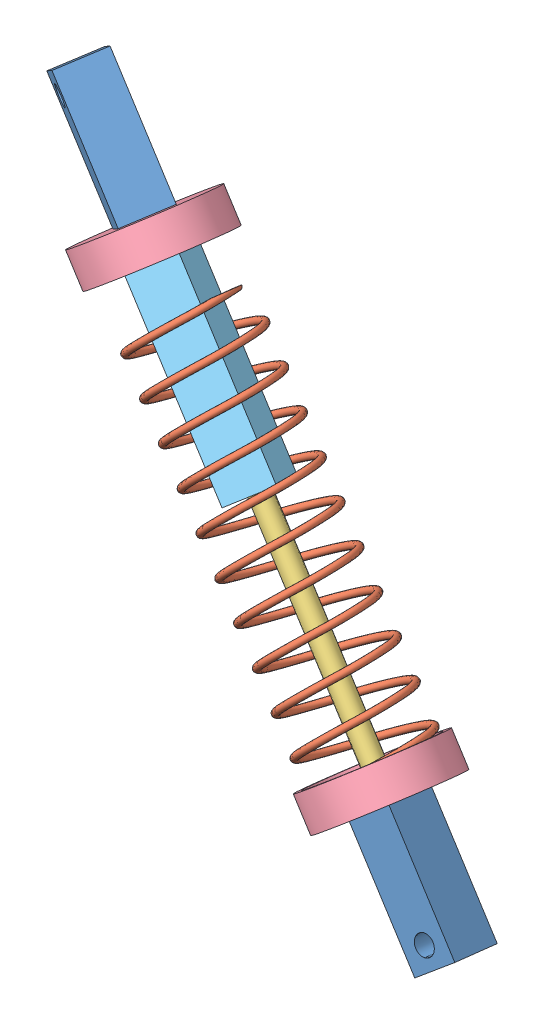
SolidWorks assembly suspension rear left, configuration Default. Lengths in mm.
Overall size (75.34 88.84 32.28).
7 component instances, 5 part files, 13 mates.
Components (placement in the parent):
- ball joint-1: ball joint [Default] at (-54.7652 66.2742 -7.6607) x (-0.630888 -0.580795 -0.514449) z (0.446553 0.270417 -0.852916) size (7 19 7)
- ball joint-2: ball joint [Default] at (-10.1518 12.2852 -1.4201) x (0.771907 0.623528 -0.123986) z (-0.039859 -0.147177 -0.988307) size (7 19 7)
- Spring-1: Spring [Default] at (-10.1518 12.2852 -1.4201) x (0.737949 0.567603 -0.365044) z (0.229913 0.297111 0.92675) size (17.25 46.09 19.28)
- suspension shaft-1: suspension shaft [Default] at (-43.145 52.212 -6.0352) x (-0.127164 -0.216957 -0.967863) z (-0.762403 -0.602808 0.235296) size (3 65 3)
- washer-1: washer [Default] at (-10.1518 12.2852 -1.4201) x (-0.555447 -0.532788 -0.638448) z (0.537502 0.355788 -0.76453) size (19 5 19)
- washer-2: washer [Default] at (-54.7652 66.2742 -7.6607) x (0.662406 0.599329 0.449469) z (0.398305 0.22639 -0.888876) size (19 5 19)
- suspension shaft 1-1: suspension shaft 1 [Default] at (-60.4755 73.1846 -8.4595) x (-0.678732 -0.498533 0.539247) z (0.369799 0.402384 0.837458) size (7 42 7)
Mates (geometry in assembly coordinates):
- Concentric3: concentric anti-aligned: cylinder of suspension shaft-1 through (-1.9035 2.3035 -0.2663) axis (-0.634485 0.767823 -0.088753) radius 1.5; cylinder of washer-1 through (-10.7862 13.053 -1.5088) axis (0.634485 -0.767823 0.088753) radius 9.5
- Concentric4: concentric aligned: cylinder of suspension shaft-1 through (-1.9035 2.3035 -0.2663) axis (-0.634485 0.767823 -0.088753) radius 1.5; cylinder of washer-2 through (-54.1307 65.5064 -7.572) axis (-0.634485 0.767823 -0.088753) radius 2.5
- Coincident4: coincident: point of ball joint-2
- Coincident8: coincident aligned: plane of Spring-1 through (-10.1518 12.2852 -1.4201) normal (0.634485 -0.767823 0.088753); plane of washer-1 through (-10.1518 12.2852 -1.4201) normal (0.634485 -0.767823 0.088753)
- Concentric7: concentric aligned: line of Spring-1 through (-10.1518 12.2852 -1.4201) axis (-0.634485 0.767823 -0.088753); cylinder of suspension shaft-1 through (-1.9035 2.3035 -0.2663) axis (-0.634485 0.767823 -0.088753) radius 1.5
- LimitDistance1: limit distance = 69.3144 mm aligned: plane of washer-1 through (-10.1518 12.2852 -1.4201) normal (0.634485 -0.767823 0.088753); plane of washer-2 through (-54.1307 65.5064 -7.572) normal (0.634485 -0.767823 0.088753)
- Coincident9: coincident anti-aligned: plane of ball joint-2 through (-5.1121 -1.7509 -12.4031) normal (-0.634485 0.767823 -0.088753); plane of suspension shaft-1 through (-1.9035 2.3035 -0.2663) normal (0.634485 -0.767823 0.088753)
- Concentric8: concentric aligned: cylinder of ball joint-2 through (-1.9035 2.3035 -0.2663) axis (-0.634485 0.767823 -0.088753) radius 2; cylinder of suspension shaft-1 through (-1.9035 2.3035 -0.2663) axis (-0.634485 0.767823 -0.088753) radius 1.5
- Coincident10: coincident anti-aligned: plane of ball joint-2 through (-10.1518 12.2852 -1.4201) normal (-0.634485 0.767823 -0.088753); plane of washer-1 through (-10.1518 12.2852 -1.4201) normal (0.634485 -0.767823 0.088753)
- Coincident11: coincident anti-aligned: plane of ball joint-1 through (-54.7652 66.2742 -7.6607) normal (0.634485 -0.767823 0.088753); plane of washer-2 through (-54.7652 66.2742 -7.6607) normal (-0.634485 0.767823 -0.088753)
- Concentric9: concentric anti-aligned: cylinder of ball joint-1 through (-63.0135 76.2559 -8.8145) axis (0.634485 -0.767823 0.088753) radius 2; cylinder of washer-2 through (-54.1307 65.5064 -7.572) axis (-0.634485 0.767823 -0.088753) radius 2.5
- Coincident12: coincident anti-aligned: plane of washer-2 through (-54.1307 65.5064 -7.572) normal (0.634485 -0.767823 0.088753); plane of suspension shaft 1-1 through (-54.1307 65.5064 -7.572) normal (-0.634485 0.767823 -0.088753)
- Concentric10: concentric aligned: cylinder of washer-2 through (-54.1307 65.5064 -7.572) axis (-0.634485 0.767823 -0.088753) radius 2.5; cylinder of suspension shaft 1-1 through (-54.1307 65.5064 -7.572) axis (-0.634485 0.767823 -0.088753) radius 2
